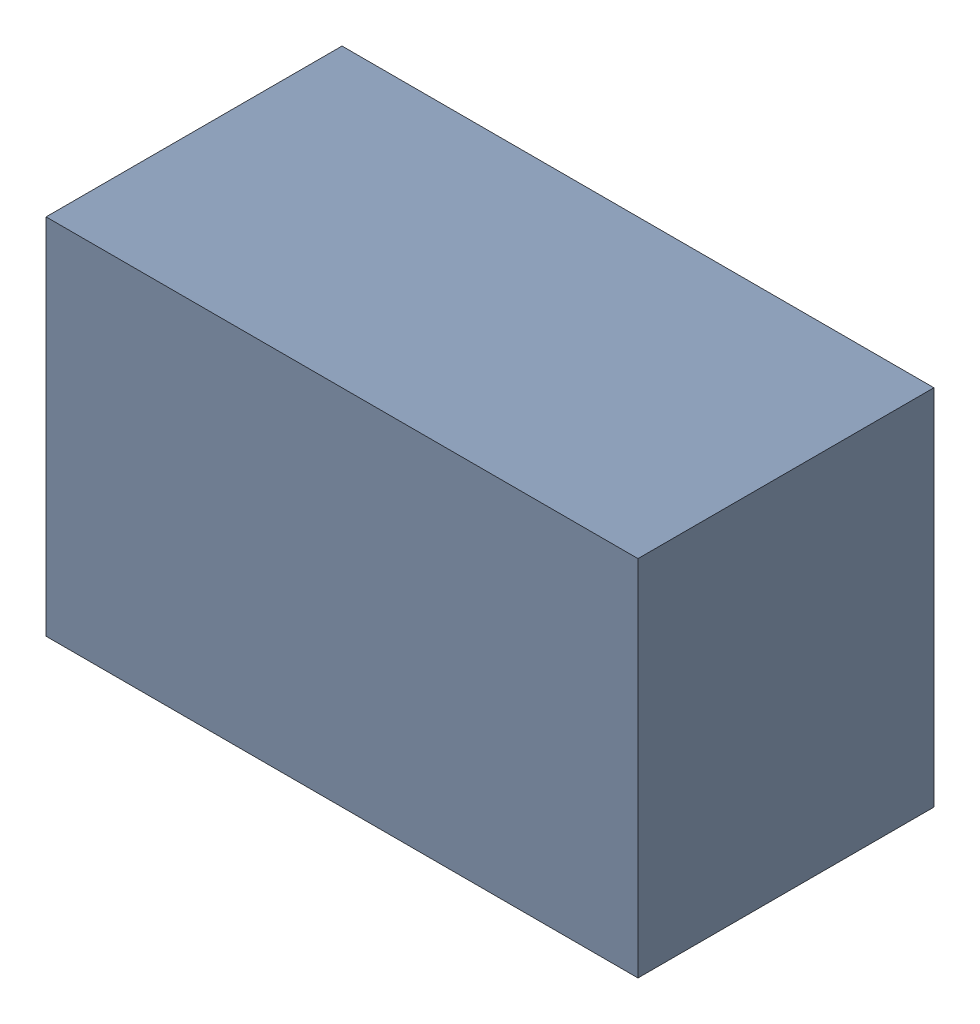
SolidWorks assembly Q9, configuration ﾃﾞﾌｫﾙﾄ. Lengths in mm.
Overall size (2.2 1.35 1.1).
2 component instances, 1 part files, 0 mates.
Components (placement in the parent):
- 689260288-1: 689260288 [ﾃﾞﾌｫﾙﾄ] at (15.25 52.75 0) size (2.2 1.35 1.1)
  - Extruded_22-1: Extruded_22 [ﾃﾞﾌｫﾙﾄ] at origin size (2.2 1.35 1.1)
